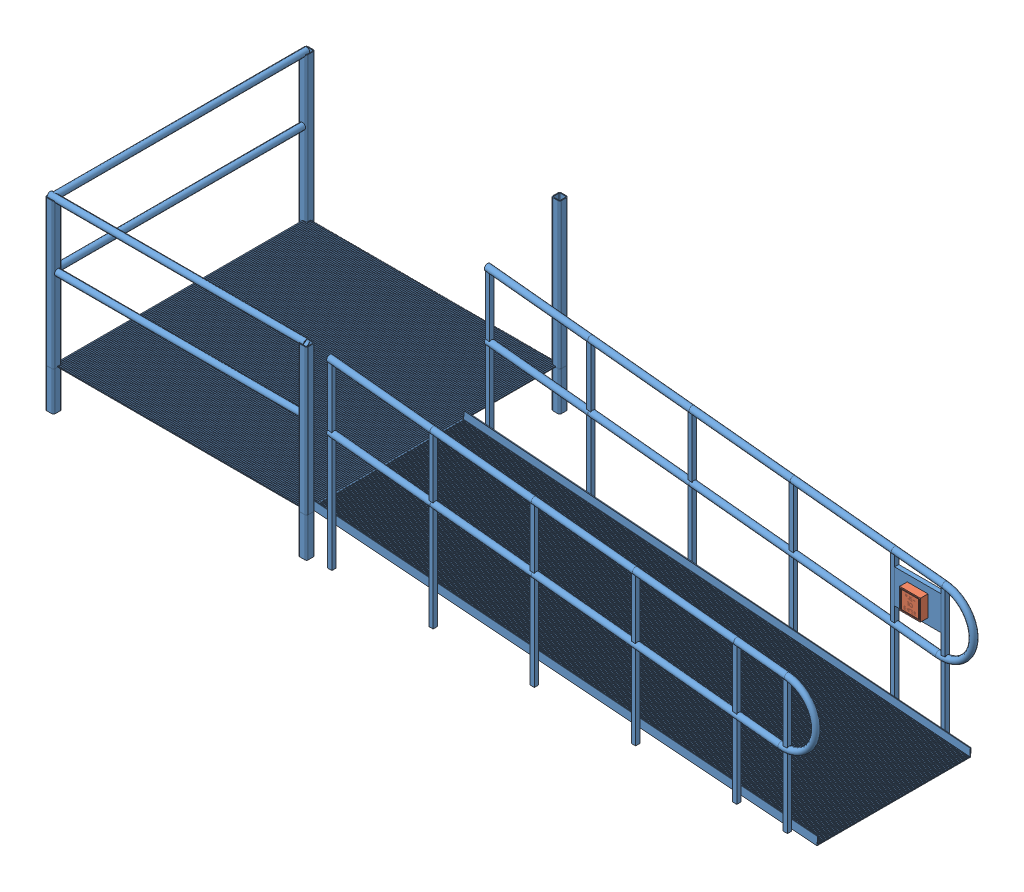
SolidWorks assembly Barrier Free Ramp, configuration Default. Lengths in mm.
Overall size (4653.49 1130.81 1574.8).
2 component instances, 2 part files, 3 mates.
Components (placement in the parent):
- Barrier Free Ramp with Handrails_AS PART-1: Barrier Free Ramp with Handrails_AS PART [Default] at origin size (4653.49 1130.81 1574.8)
- ENTER Button Switch-1: ENTER Button Switch [Default] at (3658.7683 896.1585 1181.8659) x (1 0 0) z (0 -1 0) size (124.97 45.72 124.97)
Mates (geometry in assembly coordinates):
- Coincident5: coincident anti-aligned: plane of ENTER Button Switch-1 through (3658.7683 896.1585 1181.8659) normal (0 0 -1); plane of Barrier Free Ramp with Handrails_AS PART-1 through (4066.7497 1061.2585 1181.8659) normal (0 0 1)
- Distance6: distance = 38.1 mm: plane of ENTER Button Switch-1 through (3658.7683 896.1585 1181.8659) normal (0 -1 0); line of Barrier Free Ramp with Handrails_AS PART-1 through (3861.9683 858.0585 1181.8659) axis (-1 0 0)
- Distance7: distance = 76.2 mm: plane of ENTER Button Switch-1 through (3658.7683 896.1585 1181.8659) normal (1 0 0); line of Barrier Free Ramp with Handrails_AS PART-1 through (3582.5683 1061.2585 1181.8659) axis (0 -1 0)
